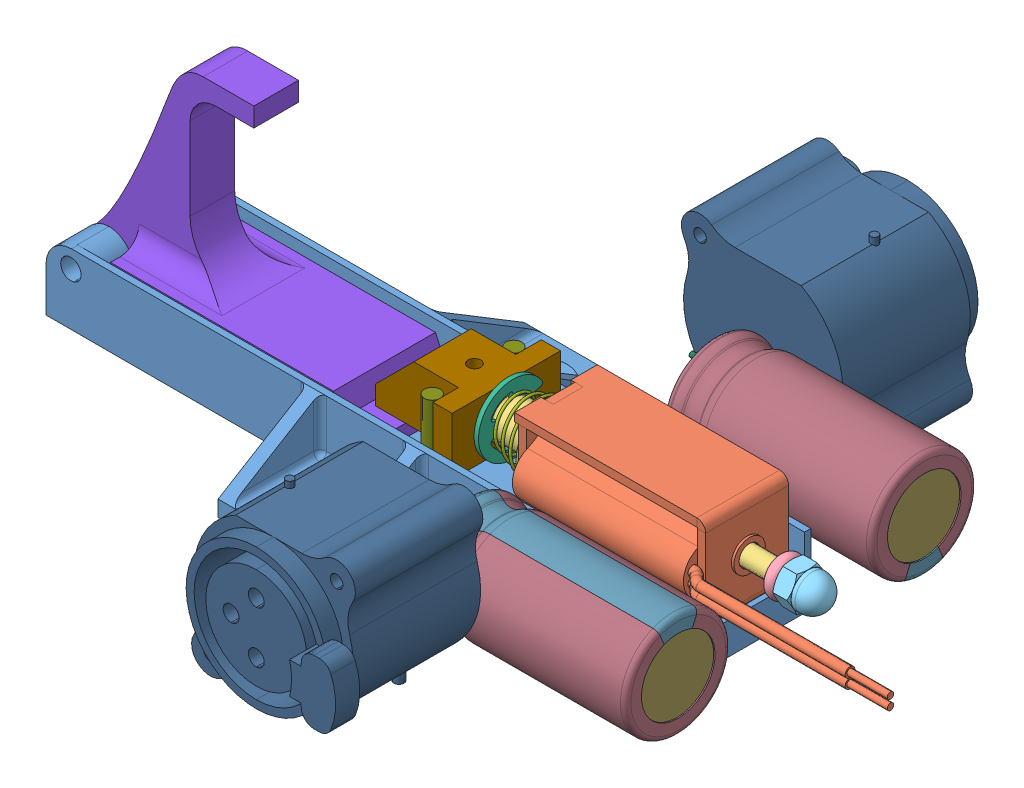
SolidWorks assembly Kabuki-asm, configuration Standard. Lengths in mm.
Overall size (131.21 38.37 109.67).
30 component instances, 17 part files, 19 mates.
Components (placement in the parent):
- Base-1: Base [Standard] at origin size (100 11 48)
- JF-0530B-1: JF-0530B [Défaut] at (35 12.5 0) x (-1 0 0) z (0 1 0) size (76.53 15.98 15) (flexible)
  - Coil-1: Coil [Défaut] at origin size (61.21 15.98 15)
  - Plunger-1: Plunger [Défaut] at (30.3268 0 0) size (57.37 6 6)
  - O-Ring-1: O-Ring [Défaut] at (-21.0091 0 0) x (0 0.369404 -0.929269) z (0 0.929269 0.369404) size (6 1.91 6)
  - M3x0,5 Cap Nut-1: M3x0,5 Cap Nut [95514A101] at (-21.9616 0 0) x (0 0 -1) z (1 0 0) size (5.5 6.35 6)
  - Circlip-1: Circlip [98543A113] at (22.0718 0 0) x (1 0 0) z (0 -1 0) size (0.7 10.85 10.07)
  - Spring-1: Spring [1692K49] at (14.365 0 0) x (0 0 -1) z (0 -1 0) size (11.99 8.45 11.92)
- latch-1: latch [Standard] at (-20.8976 10.2 0) x (1 0 0) z (0 0 -1) size (49.2 33.09 16)
- Notch-1: Notch [Standard] at (12.2132 8 -4.5) x (0 0 1) z (0 -1 0) size (17 16 9)
- d-nc3fahr1-1: d-nc3fahr1 [Default] at (23.763 14.7624 48.0749) x (0 1 0) z (0 0 -1) size (27.35 29.5 26.9)
- User Library-CapAluRadial_D160H315-1: User Library-CapAluRadial_D160H315 [Default] at (25.0517 12.3491 -19.2362) x (0 1 0) z (1 0 0) size (16.5 16.5 36.55)
  - User Library-CapAluRadial_D160H315_rubber_pad-1: User Library-CapAluRadial_D160H315_rubber_pad [Default] at origin size (11.55 11.55 1)
  - User Library-CapAluRadial_D160H315_can-1: User Library-CapAluRadial_D160H315_can [Default] at origin size (11.55 11.55 32.3)
  - User Library-CapAluRadial_D160H315_shell_and_minus-1: User Library-CapAluRadial_D160H315_shell_and_minus [Default] at origin size (16.01 16.5 32.93)
  - User Library-CapAluRadial_D160H315_shell_and_minus_2-1: User Library-CapAluRadial_D160H315_shell_and_minus_2 [Default] at origin size (2.91 6.76 32.93)
  - User Library-CapAluRadial_D160H315_lead-1: User Library-CapAluRadial_D160H315_lead [Default] at (-3.75 0 0) size (0.8 0.8 3)
  - User Library-CapAluRadial_D160H315_lead-2: User Library-CapAluRadial_D160H315_lead [Default] at (3.75 0 0) x (-1 0 0) z (0 0 1) size (0.8 0.8 3)
- User Library-CapAluRadial_D160H315-2: User Library-CapAluRadial_D160H315 [Default] at (24.9117 9.8022 19.2194) x (0 -1 0) z (1 0 0) size (16.5 16.5 36.55)
  - User Library-CapAluRadial_D160H315_rubber_pad-1: User Library-CapAluRadial_D160H315_rubber_pad [Default] at origin size (11.55 11.55 1)
  - User Library-CapAluRadial_D160H315_can-1: User Library-CapAluRadial_D160H315_can [Default] at origin size (11.55 11.55 32.3)
  - User Library-CapAluRadial_D160H315_shell_and_minus-1: User Library-CapAluRadial_D160H315_shell_and_minus [Default] at origin size (16.01 16.5 32.93)
  - User Library-CapAluRadial_D160H315_shell_and_minus_2-1: User Library-CapAluRadial_D160H315_shell_and_minus_2 [Default] at origin size (2.91 6.76 32.93)
  - User Library-CapAluRadial_D160H315_lead-1: User Library-CapAluRadial_D160H315_lead [Default] at (-3.75 0 0) size (0.8 0.8 3)
  - User Library-CapAluRadial_D160H315_lead-2: User Library-CapAluRadial_D160H315_lead [Default] at (3.75 0 0) x (-1 0 0) z (0 0 1) size (0.8 0.8 3)
- d-nc3fahr1-2: d-nc3fahr1 [Default] at (24.7213 14.4197 -47.797) x (0 1 0) z (0 0 1) size (27.35 29.5 26.9)
- countersunk flat head cross recess screw_din-2: countersunk flat head cross recess screw_din [DIN EN ISO 7046-1 - M2.5 x 16 - Z - 16N] at (7 0 -6.4) x (0 1 0) z (-0.84367 0 0.536863) size (16 4.7 4.7)
- countersunk flat head cross recess screw_din-3: countersunk flat head cross recess screw_din [DIN EN ISO 7046-1 - M2.5 x 16 - Z - 16N] at (7 0 6.4) x (0 1 0) z (0.999959 0 0.009097) size (16 4.7 4.7)
- hex nut style 1 gradeab_din-1: hex nut style 1 gradeab_din [Hexagon Nut ISO 4032 - M2.5 - D - N] at (7 3 -6.4) x (0.866025 0 -0.5) z (0 -1 0) size (5 5.77 2)
- hex nut style 1 gradeab_din-2: hex nut style 1 gradeab_din [Hexagon Nut ISO 4032 - M2.5 - D - N] at (7 3 6.4) x (0.866025 0 0.5) z (0 -1 0) size (5 5.77 2)
Mates (geometry in assembly coordinates):
- Coincident1: coordinate: point of Base-1
- Coincident2: coincident aligned: plane of Base-1 through (50 5 9) normal (1 0 0); plane of JF-0530B-1/Coil-1 through (50 20 -6.5) normal (1 0 0)
- Coincident3: coincident anti-aligned: plane of Base-1 through (0 5 0) normal (0 1 0); plane of JF-0530B-1/Coil-1 through (50 5 -6.5) normal (0 -1 0)
- Concentric2: concentric aligned: cylinder of Base-1 through (-46.0976 8.2 -10) axis (0 0 1) radius 1.6; cylinder of latch-1 through (-46.0976 8.2 -8.001) axis (0 0 1) radius 1.6
- Coincident5: coincident anti-aligned: plane of Base-1 through (0 0 0) normal (0 0 1); plane of latch-1 through (-20.8976 10.2 0) normal (0 0 -1)
- Concentric3: concentric aligned: cylinder of JF-0530B-1/Plunger-1 through (80.7045 12.5 0) axis (1 0 0) radius 3; cylinder of Notch-1 through (4.2132 12.5 0) axis (1 0 0) radius 3.1
- Concentric5: concentric aligned: cylinder of JF-0530B-1/Plunger-1 through (7.2132 9.5 0) axis (0 1 0) radius 0.7937; cylinder of Notch-1 through (7.2132 5.1716 0) axis (0 1 0) radius 1
- Concentric9: concentric anti-aligned: cylinder of Base-1 through (7 -0.001 6.4) axis (0 1 0) radius 1.6; cylinder of countersunk flat head cross recess screw_din-3 through (7 -6.35 6.4) axis (0 -1 0) radius 1.25
- Coincident8: coincident aligned: plane of Base-1 through (0 0 0) normal (0 -1 0); plane of countersunk flat head cross recess screw_din-3 through (7 0 6.4) normal (0 -1 0)
- Coincident10: coincident aligned: plane of JF-0530B-1 through (35 12.5 0) normal (0 0 1)
- Concentric11: concentric anti-aligned: cylinder of Base-1 through (7 -0.001 -6.4) axis (0 1 0) radius 1.6; cylinder of countersunk flat head cross recess screw_din-2 through (7 -6.35 -6.4) axis (0 -1 0) radius 1.25
- Coincident11: coincident aligned: plane of Base-1 through (0 0 0) normal (0 -1 0); plane of countersunk flat head cross recess screw_din-2 through (7 0 -6.4) normal (0 -1 0)
- Concentric12: concentric aligned: cylinder of countersunk flat head cross recess screw_din-2 through (7 -6.35 -6.4) axis (0 -1 0) radius 1.25; cylinder of hex nut style 1 gradeab_din-1 through (7 28.0375 -6.4) axis (0 -1 0) radius 1.25
- Concentric13: concentric aligned: cylinder of countersunk flat head cross recess screw_din-3 through (7 -6.35 6.4) axis (0 -1 0) radius 1.25; cylinder of hex nut style 1 gradeab_din-2 through (7 28.0375 6.4) axis (0 -1 0) radius 1.25
- Parallel2: parallel anti-aligned: plane of Base-1 through (16 3 -3.8) normal (0 0 -1); plane of hex nut style 1 gradeab_din-1 through (8.4434 5 -3.9) normal (0 0 1)
- Parallel3: parallel anti-aligned: plane of Base-1 through (16 3 3.8) normal (0 0 1); plane of hex nut style 1 gradeab_din-2 through (5.5566 5 3.9) normal (0 0 -1)
- Coincident12: coincident anti-aligned: plane of Base-1 through (0 3 0) normal (0 1 0); plane of hex nut style 1 gradeab_din-1 through (8.4434 3 -3.9) normal (0 -1 0)
- Coincident13: coincident anti-aligned: plane of Base-1 through (0 3 0) normal (0 1 0); plane of hex nut style 1 gradeab_din-2 through (5.5566 3 8.9) normal (0 -1 0)
- LimitAngle1: limit planar angle = 0 rad anti-aligned: plane of latch-1 through (-20.8976 5.2 0) normal (0 -1 0); plane of Base-1 through (0 5 0) normal (0 1 0)
